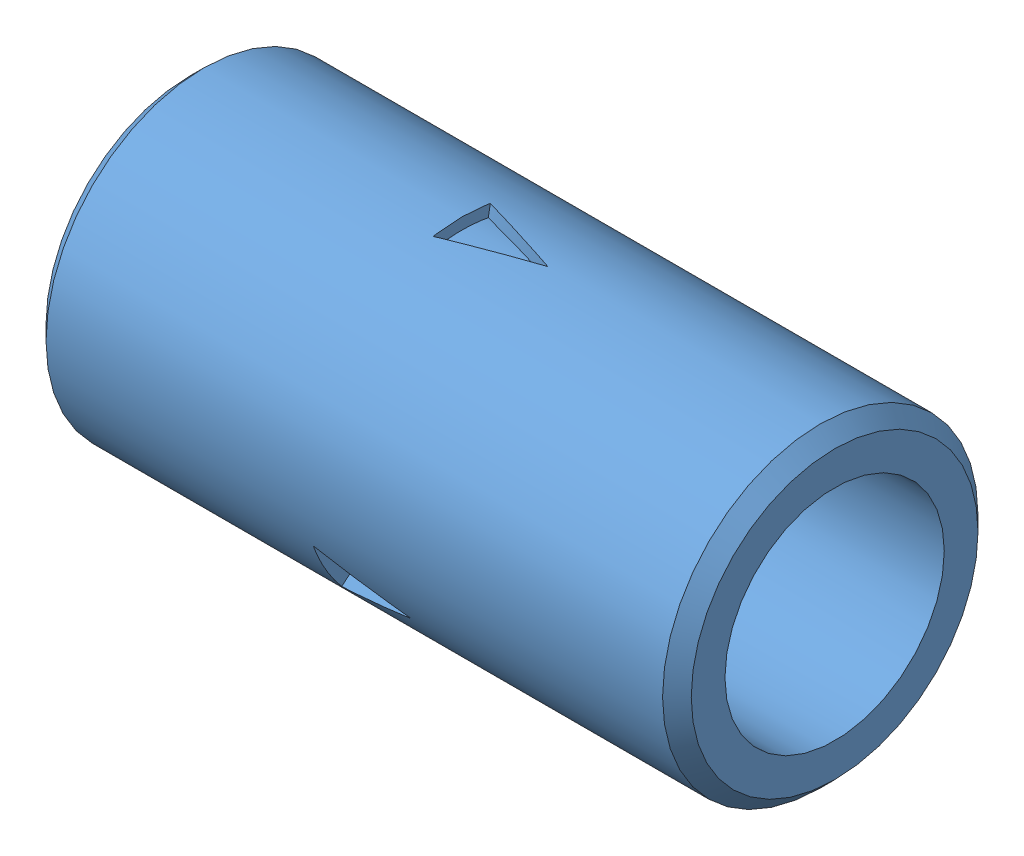
SolidWorks assembly Assem1, configuration Default. Lengths in mm.
Overall size (45 22 22).
2 component instances, 2 part files, 5 mates.
Components (placement in the parent):
- OWV-1: OWV [Default] at origin size (45 22 22)
- Umbrella Silicone-1: Umbrella Silicone [Default] at (20 0 0) x (0 -0.127687 -0.991814) z (0 -0.991814 0.127687) size (18 6 18)
Mates (geometry in assembly coordinates):
- Concentric1: concentric aligned: cylinder of OWV-1 through (25 0 0) axis (-1 0 0) radius 2.75; cylinder of Umbrella Silicone-1 through (20 0 0) axis (-1 0 0) radius 2.1
- Coincident1: coincident anti-aligned: plane of OWV-1 through (25 0 0) normal (1 0 0); plane of Umbrella Silicone-1 through (25 0.2681 2.0828) normal (-1 0 0)
- Coincident2: coincident aligned: plane of OWV-1 through (0 0 0) normal (0 0 1)
- Coincident3: coincident aligned: plane of OWV-1 through (0 0 0) normal (0 1 0)
- Coincident4: coincident aligned: plane of OWV-1 through (0 0 0) normal (1 0 0)
